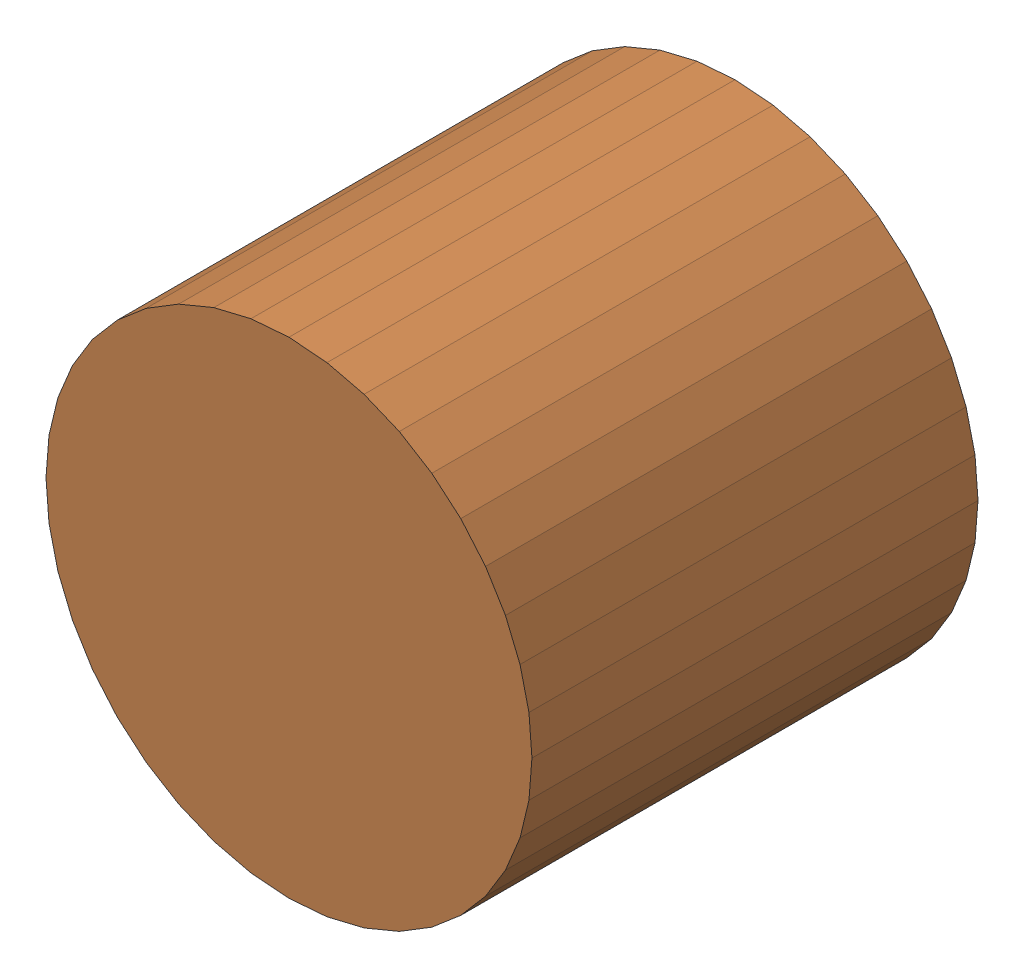
SolidWorks assembly LED2Kanaloa_v2.0.0_Motor_1, configuration Default. Lengths in mm.
Overall size (6.32 6.32 5.8).
4 component instances, 2 part files, 0 mates.
Components (placement in the parent):
- 334788912-1: 334788912 [Default] at (57.912 111.8257 0) size (1.15 1.38 0.8)
  - Extruded_31-1: Extruded_31 [Default] at origin size (1.15 1.38 0.8)
- 334789296-1: 334789296 [Default] at (57.912 111.8382 0) size (6.32 6.32 5.8)
  - Extruded_11-1: Extruded_11 [Default] at origin size (6.32 6.32 5.8)
